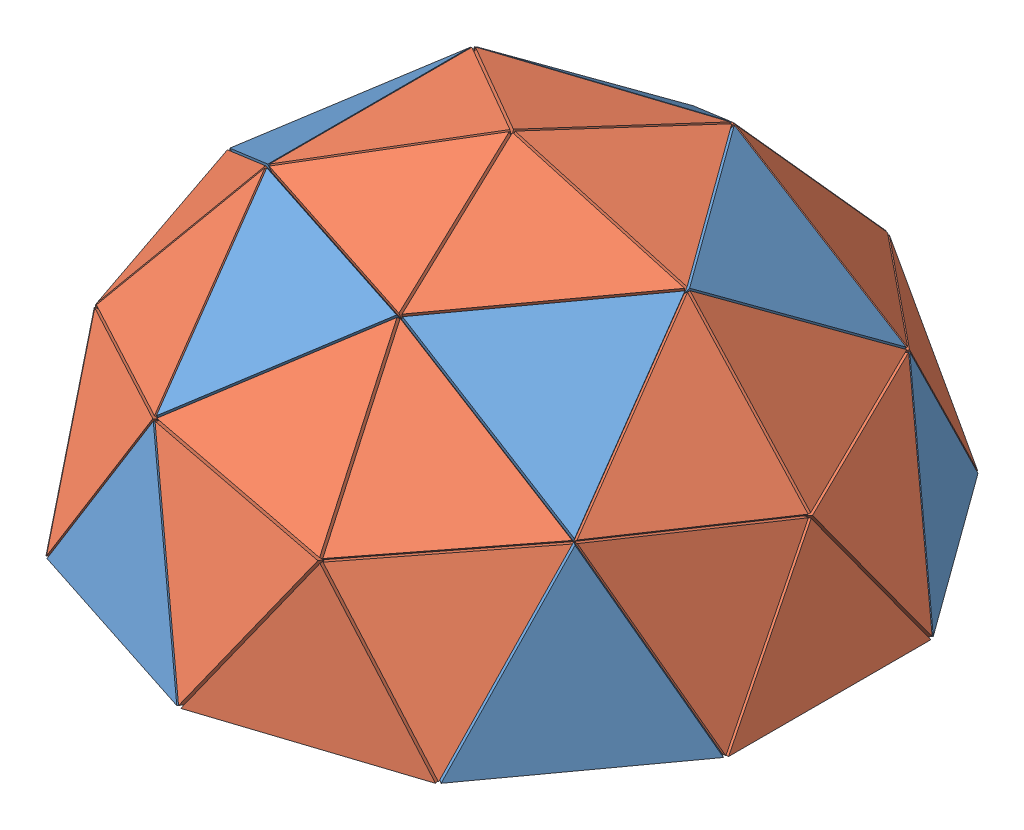
SolidWorks assembly AS_APPOLO1.1.0, configuration По умолчанию. Lengths in mm.
Overall size (6252.1 3945.78 6208.2).
40 component instances, 2 part files, 25 mates.
Components (placement in the parent):
- d1^AS_APPOLO1.1.0-1: d1^AS_APPOLO1.1.0 [По умолчанию] at (-850.6508 525.7311 2618.034) x (-0.952822 -0.059759 -0.29759) z (0.303531 -0.187592 -0.934172) size (1850.67 1659.13 60) (virtual)
- d2^AS_APPOLO1.1.0-1: d2^AS_APPOLO1.1.0 [По умолчанию] at (758.6906 2670.7024 551.221) x (-0.963409 0.262502 0.054179) z (-0.268035 -0.943522 -0.194739) size (1637.1 1559.6 60) (virtual)
- d2^AS_APPOLO1.1.0-2: d2^AS_APPOLO1.1.0 [По умолчанию] at (-289.794 2670.7024 891.8943) x (-0.349237 0.262502 -0.899514) z (0.10238 -0.943522 -0.315094) size (1637.1 1559.6 60) (virtual)
- d2^AS_APPOLO1.1.0-3: d2^AS_APPOLO1.1.0 [По умолчанию] at (-937.7931 2670.7024 0) x (0.747569 0.262502 -0.61011) z (0.331309 -0.943522 0) size (1637.1 1559.6 60) (virtual)
- d2^AS_APPOLO1.1.0-4: d2^AS_APPOLO1.1.0 [По умолчанию] at (-289.794 2670.7024 -891.8943) x (0.81126 0.262502 0.522446) z (0.10238 -0.943522 0.315094) size (1637.1 1559.6 60) (virtual)
- d2^AS_APPOLO1.1.0-5: d2^AS_APPOLO1.1.0 [По умолчанию] at (758.6906 2670.7024 -551.221) x (-0.246182 0.262502 0.932999) z (-0.268035 -0.943522 0.194739) size (1637.1 1559.6 60) (virtual)
- d1^AS_APPOLO1.1.0-2: d1^AS_APPOLO1.1.0 [По умолчанию] at (-2752.7638 525.7311 0) x (-0.011413 -0.059759 -0.998148) z (0.982247 -0.187592 0) size (1850.67 1659.13 60) (virtual)
- d1^AS_APPOLO1.1.0-3: d1^AS_APPOLO1.1.0 [По умолчанию] at (-850.6508 525.7311 -2618.034) x (0.945768 -0.059759 -0.319299) z (0.303531 -0.187592 0.934172) size (1850.67 1659.13 60) (virtual)
- d1^AS_APPOLO1.1.0-4: d1^AS_APPOLO1.1.0 [По умолчанию] at (2227.0327 525.7311 -1618.034) x (0.59593 -0.059759 0.80081) z (-0.794654 -0.187592 0.57735) size (1850.67 1659.13 60) (virtual)
- d1^AS_APPOLO1.1.0-5: d1^AS_APPOLO1.1.0 [По умолчанию] at (2227.0327 525.7311 1618.034) x (-0.577463 -0.059759 0.814227) z (-0.794654 -0.187592 -0.57735) size (1850.67 1659.13 60) (virtual)
- d1^AS_APPOLO1.1.0-6: d1^AS_APPOLO1.1.0 [По умолчанию] at (-525.7311 2227.0327 1618.034) x (0.964235 0.036933 0.262464) z (0.187592 -0.794654 -0.57735) size (1850.67 1659.13 60) (virtual)
- d2^AS_APPOLO1.1.0-6: d2^AS_APPOLO1.1.0 [По умолчанию] at (-70.0293 935.1748 2670.7024) x (0.457316 0.843008 -0.283197) z (0.02474 -0.330384 -0.943522) size (1637.1 1559.6 60) (virtual)
- d2^AS_APPOLO1.1.0-15: d2^AS_APPOLO1.1.0 [По умолчанию] at (1626.4544 935.1748 2119.4814) x (-0.734672 -0.194973 0.649802) z (-0.574604 -0.330384 -0.748783) size (1637.1 1559.6 60) (virtual)
- d2^AS_APPOLO1.1.0-23: d2^AS_APPOLO1.1.0 [По умолчанию] at (867.7638 355.5867 2670.7024) x (-0.611006 0.78604 0.093872) z (-0.306569 -0.125624 -0.943522) size (1637.1 1559.6 60) (virtual)
- d2^AS_APPOLO1.1.0-28: d2^AS_APPOLO1.1.0 [По умолчанию] at (109.0732 1872.9679 2119.4814) x (0.99391 -0.102798 0.039693) z (-0.038534 -0.661694 -0.748783) size (1637.1 1559.6 60) (virtual)
- d2^AS_APPOLO1.1.0-33: d2^AS_APPOLO1.1.0 [По умолчанию] at (1157.5578 1872.9679 1778.8081) x (0.257221 -0.744305 0.616318) z (-0.408949 -0.661694 -0.628428) size (1637.1 1559.6 60) (virtual)
- d2^AS_APPOLO1.1.0-11: d2^AS_APPOLO1.1.0 [По умолчанию] at (-2561.6291 935.1748 758.6906) x (0.410654 0.843008 0.347421) z (0.904988 -0.330384 -0.268035) size (1637.1 1559.6 60) (virtual)
- d2^AS_APPOLO1.1.0-12: d2^AS_APPOLO1.1.0 [По умолчанию] at (-1513.1446 935.1748 -2201.8058) x (-0.203517 0.843008 0.497914) z (0.534573 -0.330384 0.777868) size (1637.1 1559.6 60) (virtual)
- d2^AS_APPOLO1.1.0-13: d2^AS_APPOLO1.1.0 [По умолчанию] at (1626.4544 935.1748 -2119.4814) x (-0.536435 0.843008 -0.039693) z (-0.574604 -0.330384 0.748783) size (1637.1 1559.6 60) (virtual)
- d2^AS_APPOLO1.1.0-14: d2^AS_APPOLO1.1.0 [По умолчанию] at (2518.3486 935.1748 891.8943) x (-0.128018 0.843008 -0.522446) z (-0.889698 -0.330384 -0.315094) size (1637.1 1559.6 60) (virtual)
- d2^AS_APPOLO1.1.0-24: d2^AS_APPOLO1.1.0 [По умолчанию] at (-2271.8351 355.5867 1650.5848) x (-0.278089 0.78604 -0.552094) z (0.802608 -0.125624 -0.583129) size (1637.1 1559.6 60) (virtual)
- d2^AS_APPOLO1.1.0-25: d2^AS_APPOLO1.1.0 [По умолчанию] at (-2271.8351 355.5867 -1650.5848) x (0.439138 0.78604 -0.435084) z (0.802608 -0.125624 0.583129) size (1637.1 1559.6 60) (virtual)
- d2^AS_APPOLO1.1.0-26: d2^AS_APPOLO1.1.0 [По умолчанию] at (867.7638 355.5867 -2670.7024) x (0.549491 0.78604 0.283197) z (-0.306569 -0.125624 0.943522) size (1637.1 1559.6 60) (virtual)
- d2^AS_APPOLO1.1.0-27: d2^AS_APPOLO1.1.0 [По умолчанию] at (2808.1427 355.5867 0) x (-0.099534 0.78604 0.61011) z (-0.992078 -0.125624 0) size (1637.1 1559.6 60) (virtual)
- d2^AS_APPOLO1.1.0-19: d2^AS_APPOLO1.1.0 [По умолчанию] at (-1513.1446 935.1748 2201.8058) x (-0.845025 -0.194973 -0.497914) z (0.534573 -0.330384 -0.777868) size (1637.1 1559.6 60) (virtual)
- d2^AS_APPOLO1.1.0-20: d2^AS_APPOLO1.1.0 [По умолчанию] at (-2561.6291 935.1748 -758.6906) x (0.212418 -0.194973 -0.95753) z (0.904988 -0.330384 0.268035) size (1637.1 1559.6 60) (virtual)
- d2^AS_APPOLO1.1.0-21: d2^AS_APPOLO1.1.0 [По умолчанию] at (-70.0293 935.1748 -2670.7024) x (0.976306 -0.194973 -0.093872) z (0.02474 -0.330384 0.943522) size (1637.1 1559.6 60) (virtual)
- d2^AS_APPOLO1.1.0-22: d2^AS_APPOLO1.1.0 [По умолчанию] at (2518.3486 935.1748 -891.8943) x (0.390973 -0.194973 0.899514) z (-0.889698 -0.330384 0.315094) size (1637.1 1559.6 60) (virtual)
- d2^AS_APPOLO1.1.0-34: d2^AS_APPOLO1.1.0 [По умолчанию] at (-1334.042 1872.9679 1650.5848) x (-0.506667 -0.744305 0.435084) z (0.471299 -0.661694 -0.583129) size (1637.1 1559.6 60) (virtual)
- d2^AS_APPOLO1.1.0-35: d2^AS_APPOLO1.1.0 [По умолчанию] at (-1982.0411 1872.9679 -758.6906) x (-0.570359 -0.744305 -0.347421) z (0.700228 -0.661694 0.268035) size (1637.1 1559.6 60) (virtual)
- d2^AS_APPOLO1.1.0-36: d2^AS_APPOLO1.1.0 [По умолчанию] at (109.0732 1872.9679 -2119.4814) x (0.154166 -0.744305 -0.649802) z (-0.038534 -0.661694 0.748783) size (1637.1 1559.6 60) (virtual)
- d2^AS_APPOLO1.1.0-37: d2^AS_APPOLO1.1.0 [По умолчанию] at (2049.4521 1872.9679 -551.221) x (0.665639 -0.744305 -0.054179) z (-0.724043 -0.661694 0.194739) size (1637.1 1559.6 60) (virtual)
- d2^AS_APPOLO1.1.0-29: d2^AS_APPOLO1.1.0 [По умолчанию] at (-1982.0411 1872.9679 758.6906) x (0.269385 -0.102798 0.95753) z (0.700228 -0.661694 -0.268035) size (1637.1 1559.6 60) (virtual)
- d2^AS_APPOLO1.1.0-30: d2^AS_APPOLO1.1.0 [По умолчанию] at (-1334.042 1872.9679 -1650.5848) x (-0.827421 -0.102798 0.552094) z (0.471299 -0.661694 0.583129) size (1637.1 1559.6 60) (virtual)
- d2^AS_APPOLO1.1.0-31: d2^AS_APPOLO1.1.0 [По умолчанию] at (1157.5578 1872.9679 -1778.8081) x (-0.780759 -0.102798 -0.616318) z (-0.408949 -0.661694 0.628428) size (1637.1 1559.6 60) (virtual)
- d2^AS_APPOLO1.1.0-32: d2^AS_APPOLO1.1.0 [По умолчанию] at (2049.4521 1872.9679 551.221) x (0.344885 -0.102798 -0.932999) z (-0.724043 -0.661694 -0.194739) size (1637.1 1559.6 60) (virtual)
- d1^AS_APPOLO1.1.0-7: d1^AS_APPOLO1.1.0 [По умолчанию] at (-1701.3016 2227.0327 0) x (0.048346 0.036933 0.998148) z (0.607062 -0.794654 0) size (1850.67 1659.13 60) (virtual)
- d1^AS_APPOLO1.1.0-8: d1^AS_APPOLO1.1.0 [По умолчанию] at (-525.7311 2227.0327 -1618.034) x (-0.934355 0.036933 0.354425) z (0.187592 -0.794654 0.57735) size (1850.67 1659.13 60) (virtual)
- d1^AS_APPOLO1.1.0-9: d1^AS_APPOLO1.1.0 [По умолчанию] at (1376.3819 2227.0327 -1000) x (-0.62581 0.036933 -0.779101) z (-0.491123 -0.794654 0.356822) size (1850.67 1659.13 60) (virtual)
- d1^AS_APPOLO1.1.0-10: d1^AS_APPOLO1.1.0 [По умолчанию] at (1376.3819 2227.0327 1000) x (0.547583 0.036933 -0.835936) z (-0.491123 -0.794654 -0.356822) size (1850.67 1659.13 60) (virtual)
Mates (geometry in assembly coordinates):
- На месте1: in place: plane of ? through (-70.8876 43.8109 218.1695) normal (0.303531 -0.187592 -0.934172); moOrthogonalPlaneRef_w of ?; unknown of ?; unknown of d1^AS_APPOLO1.1.0-1
- Совпадение1: coincident: plane of assembly; plane of d1^AS_APPOLO1.1.0-1; plane of assembly
- Совпадение2: coincident: plane of assembly; plane of d1^AS_APPOLO1.1.0-1 through (-850.6508 525.7311 2618.034) normal (0 0.980427 -0.196881); moOrthogonalPlaneRef_w of assembly
- Совпадение3: coincident: plane of assembly; plane of d1^AS_APPOLO1.1.0-1 through (-850.6508 525.7311 2618.034) normal (-0.952822 -0.059759 -0.29759); moOrthogonalPlaneRef_w of assembly
- На месте2: in place: plane of ? through (63.2242 222.5585 45.9351) normal (-0.268035 -0.943522 -0.194739); unknown of ?; unknown of ?; unknown of d2^AS_APPOLO1.1.0-1
- Совпадение4: coincident: plane of assembly; plane of d2^AS_APPOLO1.1.0-1; plane of assembly
- Совпадение5: coincident: plane of assembly; plane of d2^AS_APPOLO1.1.0-1 through (758.6906 2670.7024 551.221) normal (0 0.202135 -0.979358); moOrthogonalPlaneRef_w of assembly
- Совпадение6: coincident: plane of assembly; plane of d2^AS_APPOLO1.1.0-1 through (758.6906 2670.7024 551.221) normal (-0.963409 0.262502 0.054179); moOrthogonalPlaneRef_w of assembly
- Совпадение8: coincident: point of assembly; point of assembly; point of d2^AS_APPOLO1.1.0-2; point of d1^AS_APPOLO1.1.0-6
- Совпадение11: coincident: point of assembly; point of assembly; point of d2^AS_APPOLO1.1.0-2; point of d1^AS_APPOLO1.1.0-6
- Совпадение12: coincident: point of assembly; point of assembly; point of d1^AS_APPOLO1.1.0-1; point of d1^AS_APPOLO1.1.0-6
- Совпадение13: coincident: point of assembly; point of assembly; point of d1^AS_APPOLO1.1.0-1; point of d2^AS_APPOLO1.1.0-6
- Совпадение15: coincident: unknown of d2^AS_APPOLO1.1.0-6
- Совпадение16: coincident: point of assembly; point of d2^AS_APPOLO1.1.0-15; point of assembly
- Совпадение17: coincident: unknown of d1^AS_APPOLO1.1.0-5; unknown of d2^AS_APPOLO1.1.0-15
- Совпадение18: coincident: unknown of d2^AS_APPOLO1.1.0-6; unknown of d2^AS_APPOLO1.1.0-15
- Совпадение23: coincident: point of assembly; point of d2^AS_APPOLO1.1.0-23; point of assembly
- Совпадение24: coincident: unknown of d2^AS_APPOLO1.1.0-23
- Совпадение25: coincident: unknown of d2^AS_APPOLO1.1.0-15; unknown of d2^AS_APPOLO1.1.0-23
- Совпадение26: coincident: point of assembly; point of assembly; point of d2^AS_APPOLO1.1.0-1; point of d2^AS_APPOLO1.1.0-28
- Совпадение27: coincident: unknown of d1^AS_APPOLO1.1.0-1; unknown of d2^AS_APPOLO1.1.0-28
- Совпадение28: coincident: unknown of d2^AS_APPOLO1.1.0-15; unknown of d2^AS_APPOLO1.1.0-28
- Совпадение29: coincident: unknown of d2^AS_APPOLO1.1.0-28; unknown of d2^AS_APPOLO1.1.0-33
- Совпадение30: coincident: unknown of d2^AS_APPOLO1.1.0-15; unknown of d2^AS_APPOLO1.1.0-33
- Совпадение31: coincident: unknown of d2^AS_APPOLO1.1.0-28; unknown of d2^AS_APPOLO1.1.0-33
